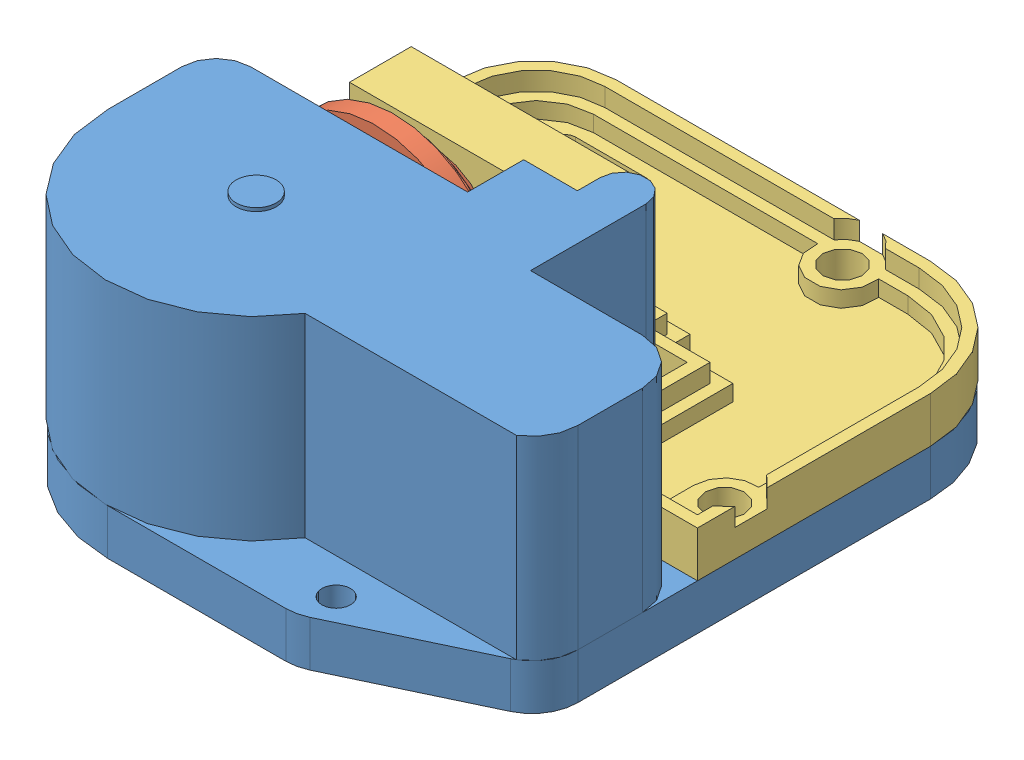
SolidWorks assembly muziekdoos, configuration Default. Lengths in mm.
Overall size (44.96 26.92 50.5).
3 component instances, 3 part files, 6 mates.
Components (placement in the parent):
- muziekdoos_spring_housing-1: muziekdoos_spring_housing [Default] at (-60.1621 -3.9837 16.6882) size (44.5 21.3 50.5)
- muziekdoos_main_gear-1: muziekdoos_main_gear [Default] at (-71.5908 7.5163 30.2693) x (-0.793771 -0.608216 0) z (0.608216 -0.793771 0) size (19.2 7.2 19.2)
- PCB_floor2-1: PCB_floor2 [Default] at (-60.1621 0.0163 16.6882) x (1 0 0) z (0 1 0) size (44.5 30.4 14)
Mates (geometry in assembly coordinates):
- Concentric1: concentric aligned: cylinder of muziekdoos_spring_housing-1 through (-71.5908 7.5163 32.2193) axis (0 0 -1) radius 1.25; cylinder of muziekdoos_main_gear-1 through (-71.5908 7.5163 43.3756) axis (0 0 -1) radius 1.275
- Distance1: distance = 28.35 mm anti-aligned: plane of muziekdoos_main_gear-1 through (-71.5908 7.5163 25.3693) normal (0 0 -1); plane of muziekdoos_spring_housing-1 through (-71.5908 0.0163 53.7193) normal (0 0 1)
- InPlace1: in place: plane of muziekdoos_spring_housing-1 through (-50.0908 0.0163 13.2193) normal (0 1 0); plane of ? through (0 0.0163 0) normal (0 1 0); moOrthogonalPlaneRef_w of muziekdoos_spring_housing-1 through (-50.0908 0.0163 13.2193) normal (0 1 0); plane of ? through (0 0.0163 0) normal (0 0 -1); plane of muziekdoos_spring_housing-1 through (-50.0908 0.0163 13.2193) normal (0 1 0); plane of ? through (0 0.0163 0) normal (1 0 0); plane of muziekdoos_spring_housing-1 through (-50.0908 0.0163 13.2193) normal (0 1 0); unknown of PCB_floor2-1
- Coincident2: coincident aligned: plane of muziekdoos_spring_housing-1; plane of PCB_floor2-1
- Coincident3: coincident aligned: moOrthogonalPlaneRef_w of muziekdoos_spring_housing-1 through (-60.1621 0.0163 16.6882) normal (0 0 -1); plane of PCB_floor2-1 through (-60.1621 0.0163 16.6882) normal (0 0 -1)
- Coincident4: coincident anti-aligned: moOrthogonalPlaneRef_w of muziekdoos_spring_housing-1 through (-60.1621 0.0163 16.6882) normal (-1 0 0); plane of PCB_floor2-1 through (-60.1621 0.0163 16.6882) normal (1 0 0)
